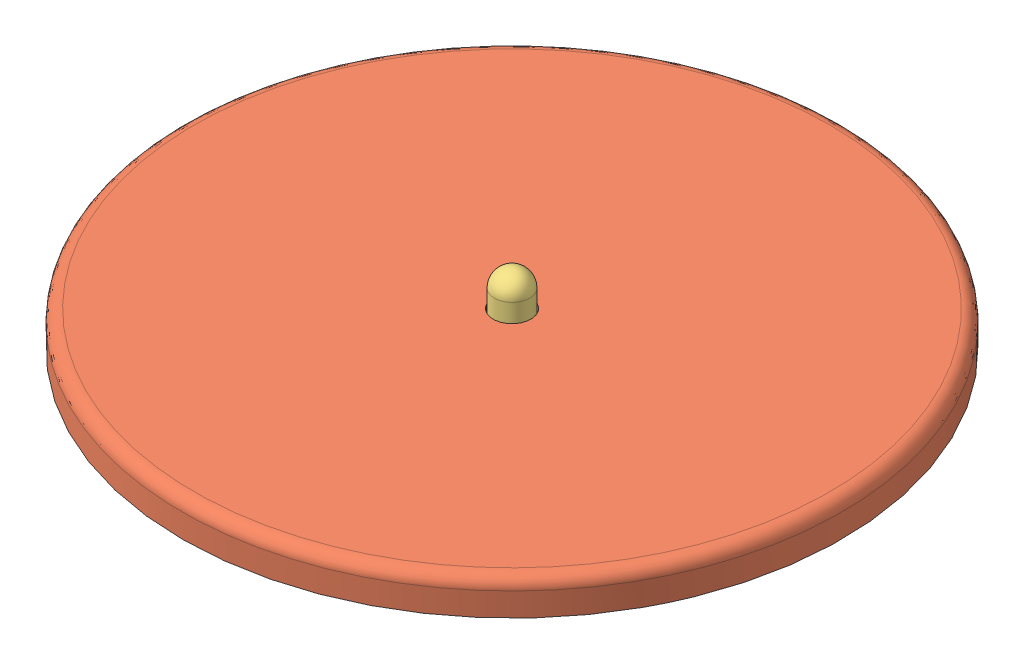
SolidWorks assembly plate_lp60, configuration Default. Lengths in mm.
Overall size (372.85 50 372.85).
3 component instances, 3 part files, 5 mates.
Components (placement in the parent):
- disk_padding-1: disk_padding [Default] at (-20.6874 21.0765 1.1138) size (275 10 275)
- metal_disk-1: metal_disk [Default] at (-20.6874 21.0765 1.1138) x (0.427647 0 -0.903946) z (0.903946 0 0.427647) size (280 15 280)
- spindle_lp60-1: spindle_lp60 [Default] at (-20.6874 26.0765 1.1138) x (-0.903557 0 0.428468) z (-0.428468 0 -0.903557) size (15 50 15)
Mates (geometry in assembly coordinates):
- Coincident2: coincident aligned: plane of disk_padding-1 through (-20.6874 21.0765 1.1138) normal (0 -1 0); plane of metal_disk-1 through (-20.6874 21.0765 1.1138) normal (0 -1 0)
- Concentric3: concentric aligned: cylinder of disk_padding-1 through (-20.6874 21.0765 1.1138) axis (0 1 0) radius 8; cylinder of metal_disk-1 through (-20.6874 21.0765 1.1138) axis (0 1 0) radius 8
- Concentric4: concentric aligned: cylinder of metal_disk-1 through (-20.6874 21.0765 1.1138) axis (0 1 0) radius 8; cylinder of spindle_lp60-1 through (-20.6874 43.5765 1.1138) axis (0 1 0) radius 7.5
- Distance3: distance = 0 mm anti-aligned: sphere of spindle_lp60-1; plane of metal_disk-1 through (-20.6874 36.0765 1.1138) normal (0 1 0)
- Concentric7: concentric aligned: cylinder of metal_disk-1 through (-20.6874 21.0765 1.1138) axis (0 1 0) radius 8; cylinder of spindle_lp60-1 through (-20.6874 43.5765 1.1138) axis (0 1 0) radius 7.5
